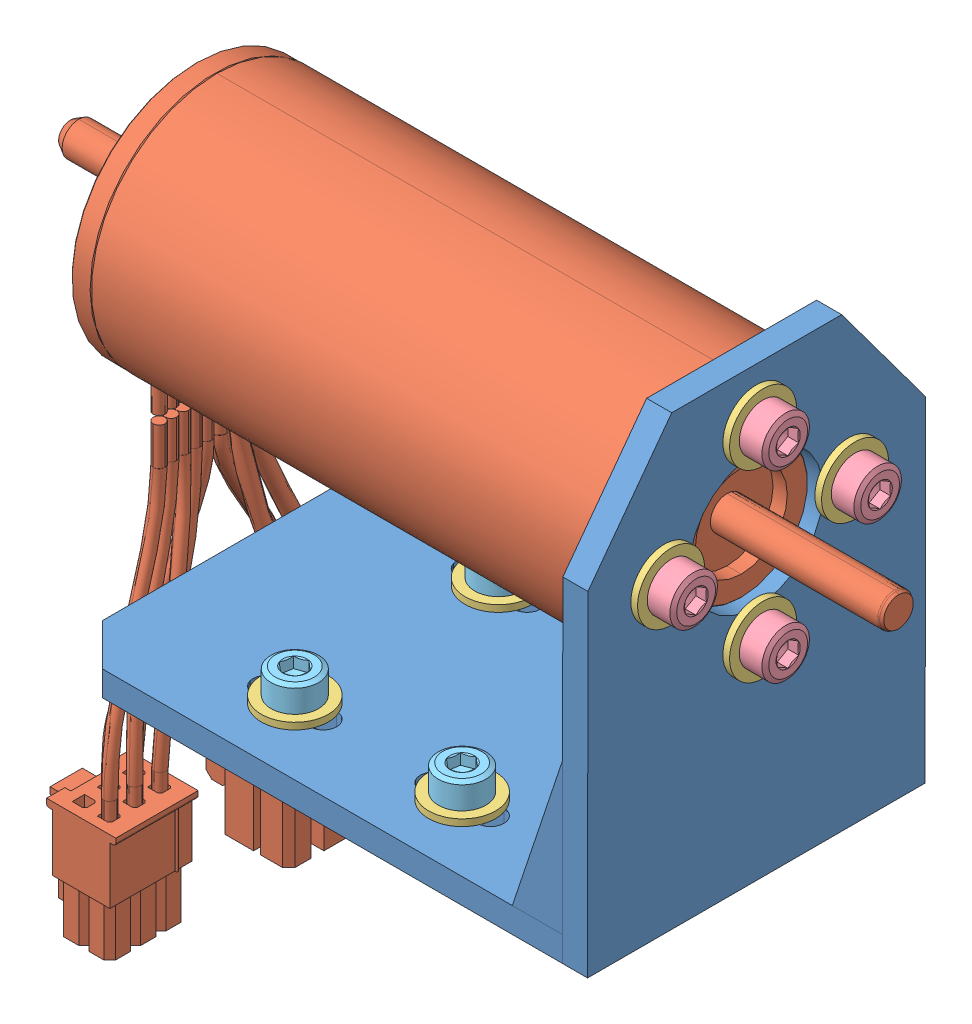
SolidWorks assembly Dc_Brushless_Assembly, configuration Default. Lengths in mm.
Overall size (99 86.67 40.4).
18 component instances, 5 part files, 35 mates.
Components (placement in the parent):
- DC_Brushless_mount-1: DC_Brushless_mount [Default] at (31.1622 81.4943 68.2509) x (0 0 1) z (0 -1 0) size (40.4 63 53.49)
- DC_Brushless_272762_ec-max30_60w.stp-1: DC_Brushless_272762_ec-max30_60w.stp [Default] at (19.2622 35.7216 38.1991) x (-1 0 0) z (0 0 -1) size (99 84.66 30.24)
- M3_95610A330_Nylon Plastic Washer-1: M3_95610A330_Nylon Plastic Washer [95610A330] at (31.5622 24.7216 38.1991) x (0 0.253843 0.967245) z (-1 0 0) size (8 8 0.8)
- M3_95610A330_Nylon Plastic Washer-2: M3_95610A330_Nylon Plastic Washer [95610A330] at (31.5622 35.7216 27.1991) x (0 0.155172 0.987888) z (-1 0 0) size (8 8 0.8)
- M3_95610A330_Nylon Plastic Washer-3: M3_95610A330_Nylon Plastic Washer [95610A330] at (31.5622 46.7216 38.1991) x (0 0 1) z (-1 0 0) size (8 8 0.8)
- M3_95610A330_Nylon Plastic Washer-4: M3_95610A330_Nylon Plastic Washer [95610A330] at (31.5622 35.7216 49.1991) x (0 0.252411 0.96762) z (-1 0 0) size (8 8 0.8)
- M3_8mm_98511A729_Aluminum Socket Head Screw (1)-1: M3_8mm_98511A729_Aluminum Socket Head Screw (1) [98511A729] at (29.4622 24.7216 38.1991) size (11.32 5.68 5.68)
- M3_8mm_98511A729_Aluminum Socket Head Screw (1)-2: M3_8mm_98511A729_Aluminum Socket Head Screw (1) [98511A729] at (29.4622 35.7216 49.1991) size (11.32 5.68 5.68)
- M3_8mm_98511A729_Aluminum Socket Head Screw (1)-3: M3_8mm_98511A729_Aluminum Socket Head Screw (1) [98511A729] at (29.4622 46.7216 38.1991) size (11.32 5.68 5.68)
- M3_8mm_98511A729_Aluminum Socket Head Screw (1)-4: M3_8mm_98511A729_Aluminum Socket Head Screw (1) [98511A729] at (29.4622 35.7216 27.1991) size (11.32 5.68 5.68)
- M3_95610A330_Nylon Plastic Washer-5: M3_95610A330_Nylon Plastic Washer [95610A330] at (8.1622 2.8005 50.3742) x (0.855074 0 0.518506) z (0 -1 0) size (8 8 0.8)
- M3_95610A330_Nylon Plastic Washer-6: M3_95610A330_Nylon Plastic Washer [95610A330] at (-11.8378 2.8005 50.3742) x (0.983199 0 -0.182536) z (0 -1 0) size (8 8 0.8)
- M3_95610A330_Nylon Plastic Washer-7: M3_95610A330_Nylon Plastic Washer [95610A330] at (8.1622 2.8005 26.0208) x (0.851879 0 0.523738) z (0 -1 0) size (8 8 0.8)
- M3_95610A330_Nylon Plastic Washer-8: M3_95610A330_Nylon Plastic Washer [95610A330] at (-11.8378 2.8005 26.0208) x (0.977128 0 0.212653) z (0 -1 0) size (8 8 0.8)
- M3_10mm_98511A731_Aluminum Socket Head Screw-1: M3_10mm_98511A731_Aluminum Socket Head Screw [98511A731] at (8.1622 -0.2995 50.3742) x (0 1 0) z (0.631898 0 -0.775052) size (13.33 5.68 5.68)
- M3_10mm_98511A731_Aluminum Socket Head Screw-2: M3_10mm_98511A731_Aluminum Socket Head Screw [98511A731] at (8.1622 -0.2995 26.0208) x (0 1 0) z (0.638158 0 0.769905) size (13.33 5.68 5.68)
- M3_10mm_98511A731_Aluminum Socket Head Screw-3: M3_10mm_98511A731_Aluminum Socket Head Screw [98511A731] at (-11.8378 -0.2995 50.3742) x (0 1 0) z (0.983429 0 0.181292) size (13.33 5.68 5.68)
- M3_10mm_98511A731_Aluminum Socket Head Screw-4: M3_10mm_98511A731_Aluminum Socket Head Screw [98511A731] at (-11.8378 -0.2995 26.0208) x (0 1 0) z (-0.583552 0 -0.812076) size (13.33 5.68 5.68)
Mates (geometry in assembly coordinates):
- Concentric1: concentric aligned: cylinder of DC_Brushless_mount-1 through (28.1622 35.7216 38.1991) axis (1 0 0) radius 8; cylinder of DC_Brushless_272762_ec-max30_60w.stp-1 through (18.7572 35.7216 38.1991) axis (1 0 0) radius 8
- Concentric2: concentric aligned: cylinder of DC_Brushless_mount-1 through (28.1622 46.7216 38.1991) axis (1 0 0) radius 1.6; cylinder of DC_Brushless_272762_ec-max30_60w.stp-1 through (17.7567 46.7216 38.1991) axis (1 0 0) radius 1.25
- Coincident1: coincident anti-aligned: plane of DC_Brushless_mount-1 through (28.1622 81.4943 68.2509) normal (-1 0 0); plane of DC_Brushless_272762_ec-max30_60w.stp-1 through (28.1622 35.7216 38.1991) normal (1 0 0)
- Concentric3: concentric aligned: cylinder of M3_95610A330_Nylon Plastic Washer-4 through (31.1622 35.7216 49.1991) axis (1 0 0) radius 1.6; cylinder of M3_8mm_98511A729_Aluminum Socket Head Screw (1)-2 through (34.9622 35.7216 49.1991) axis (1 0 0) radius 1.5
- Concentric4: concentric aligned: cylinder of M3_95610A330_Nylon Plastic Washer-3 through (31.1622 46.7216 38.1991) axis (1 0 0) radius 1.6; cylinder of M3_8mm_98511A729_Aluminum Socket Head Screw (1)-3 through (34.9622 46.7216 38.1991) axis (1 0 0) radius 1.5
- Concentric5: concentric aligned: cylinder of M3_95610A330_Nylon Plastic Washer-1 through (31.1622 24.7216 38.1991) axis (1 0 0) radius 1.6; cylinder of M3_8mm_98511A729_Aluminum Socket Head Screw (1)-1 through (34.9622 24.7216 38.1991) axis (1 0 0) radius 1.5
- Concentric6: concentric aligned: cylinder of M3_95610A330_Nylon Plastic Washer-2 through (31.1622 35.7216 27.1991) axis (1 0 0) radius 1.6; cylinder of M3_8mm_98511A729_Aluminum Socket Head Screw (1)-4 through (34.9622 35.7216 27.1991) axis (1 0 0) radius 1.5
- Coincident3: coincident anti-aligned: plane of M3_95610A330_Nylon Plastic Washer-2 through (31.9622 35.7216 27.1991) normal (1 0 0); plane of M3_8mm_98511A729_Aluminum Socket Head Screw (1)-4 through (31.9622 38.5616 27.1991) normal (-1 0 0)
- Coincident4: coincident anti-aligned: plane of M3_95610A330_Nylon Plastic Washer-1 through (31.9622 24.7216 38.1991) normal (1 0 0); plane of M3_8mm_98511A729_Aluminum Socket Head Screw (1)-1 through (31.9622 27.5616 38.1991) normal (-1 0 0)
- Coincident5: coincident anti-aligned: plane of M3_95610A330_Nylon Plastic Washer-3 through (31.9622 46.7216 38.1991) normal (1 0 0); plane of M3_8mm_98511A729_Aluminum Socket Head Screw (1)-3 through (31.9622 49.5616 38.1991) normal (-1 0 0)
- Coincident6: coincident anti-aligned: plane of M3_95610A330_Nylon Plastic Washer-4 through (31.9622 35.7216 49.1991) normal (1 0 0); plane of M3_8mm_98511A729_Aluminum Socket Head Screw (1)-2 through (31.9622 38.5616 49.1991) normal (-1 0 0)
- Concentric7: concentric aligned: cylinder of DC_Brushless_mount-1 through (28.1622 35.7216 49.1991) axis (1 0 0) radius 1.6; cylinder of M3_8mm_98511A729_Aluminum Socket Head Screw (1)-2 through (34.9622 35.7216 49.1991) axis (1 0 0) radius 1.5
- Concentric8: concentric aligned: cylinder of DC_Brushless_mount-1 through (28.1622 46.7216 38.1991) axis (1 0 0) radius 1.6; cylinder of M3_8mm_98511A729_Aluminum Socket Head Screw (1)-3 through (34.9622 46.7216 38.1991) axis (1 0 0) radius 1.5
- Concentric9: concentric aligned: cylinder of DC_Brushless_272762_ec-max30_60w.stp-1 through (17.7567 35.7216 27.1991) axis (1 0 0) radius 1.25; cylinder of M3_8mm_98511A729_Aluminum Socket Head Screw (1)-4 through (34.9622 35.7216 27.1991) axis (1 0 0) radius 1.5
- Concentric10: concentric aligned: cylinder of DC_Brushless_272762_ec-max30_60w.stp-1 through (17.7567 24.7216 38.1991) axis (1 0 0) radius 1.25; cylinder of M3_8mm_98511A729_Aluminum Socket Head Screw (1)-1 through (34.9622 24.7216 38.1991) axis (1 0 0) radius 1.5
- Coincident7: coincident anti-aligned: plane of DC_Brushless_mount-1 through (31.1622 81.4943 68.2509) normal (1 0 0); plane of M3_95610A330_Nylon Plastic Washer-1 through (31.1622 24.7216 38.1991) normal (-1 0 0)
- Coincident8: coincident anti-aligned: plane of DC_Brushless_mount-1 through (31.1622 81.4943 68.2509) normal (1 0 0); plane of M3_95610A330_Nylon Plastic Washer-4 through (31.1622 35.7216 49.1991) normal (-1 0 0)
- Coincident9: coincident anti-aligned: plane of DC_Brushless_mount-1 through (31.1622 81.4943 68.2509) normal (1 0 0); plane of M3_95610A330_Nylon Plastic Washer-2 through (31.1622 35.7216 27.1991) normal (-1 0 0)
- Coincident10: coincident anti-aligned: plane of DC_Brushless_mount-1 through (31.1622 81.4943 68.2509) normal (1 0 0); plane of M3_95610A330_Nylon Plastic Washer-3 through (31.1622 46.7216 38.1991) normal (-1 0 0)
- Concentric11: concentric aligned: cylinder of M3_95610A330_Nylon Plastic Washer-7 through (8.1622 2.4005 26.0208) axis (0 1 0) radius 1.6; cylinder of M3_10mm_98511A731_Aluminum Socket Head Screw-2 through (8.1622 6.2005 26.0208) axis (0 1 0) radius 1.5
- Concentric12: concentric aligned: cylinder of M3_95610A330_Nylon Plastic Washer-5 through (8.1622 2.4005 50.3742) axis (0 1 0) radius 1.6; cylinder of M3_10mm_98511A731_Aluminum Socket Head Screw-1 through (8.1622 6.2005 50.3742) axis (0 1 0) radius 1.5
- Concentric13: concentric aligned: cylinder of M3_95610A330_Nylon Plastic Washer-8 through (-11.8378 2.4005 26.0208) axis (0 1 0) radius 1.6; cylinder of M3_10mm_98511A731_Aluminum Socket Head Screw-4 through (-11.8378 6.2005 26.0208) axis (0 1 0) radius 1.5
- Concentric14: concentric aligned: cylinder of M3_95610A330_Nylon Plastic Washer-6 through (-11.8378 2.4005 50.3742) axis (0 1 0) radius 1.6; cylinder of M3_10mm_98511A731_Aluminum Socket Head Screw-3 through (-11.8378 6.2005 50.3742) axis (0 1 0) radius 1.5
- Coincident11: coincident anti-aligned: plane of M3_95610A330_Nylon Plastic Washer-7 through (8.1622 3.2005 26.0208) normal (0 1 0); plane of M3_10mm_98511A731_Aluminum Socket Head Screw-2 through (5.9757 3.2005 27.8332) normal (0 -1 0)
- Coincident12: coincident anti-aligned: plane of M3_95610A330_Nylon Plastic Washer-5 through (8.1622 3.2005 50.3742) normal (0 1 0); plane of M3_10mm_98511A731_Aluminum Socket Head Screw-1 through (10.3634 3.2005 52.1688) normal (0 -1 0)
- Coincident13: coincident anti-aligned: plane of M3_95610A330_Nylon Plastic Washer-8 through (-11.8378 3.2005 26.0208) normal (0 1 0); plane of M3_10mm_98511A731_Aluminum Socket Head Screw-4 through (-9.5315 3.2005 24.3635) normal (0 -1 0)
- Coincident14: coincident anti-aligned: plane of M3_95610A330_Nylon Plastic Washer-6 through (-11.8378 3.2005 50.3742) normal (0 1 0); plane of M3_10mm_98511A731_Aluminum Socket Head Screw-3 through (-12.3526 3.2005 53.1672) normal (0 -1 0)
- Slot1: slot: cylinder of M3_10mm_98511A731_Aluminum Socket Head Screw-2 through (8.1622 6.2005 26.0208) axis (0 1 0) radius 1.5; plane of DC_Brushless_mount-1 through (4.7622 -0.7995 27.6208) normal (0 0 -1); cylinder of DC_Brushless_mount-1 through (4.7622 2.4005 26.0208) axis (0 1 0) radius 1.6
- Coincident15: coincident anti-aligned: plane of DC_Brushless_mount-1 through (-31.8378 2.4005 18.0208) normal (0 1 0); plane of M3_95610A330_Nylon Plastic Washer-7 through (8.1622 2.4005 26.0208) normal (0 -1 0)
- Coincident16: coincident anti-aligned: plane of DC_Brushless_mount-1 through (-31.8378 2.4005 18.0208) normal (0 1 0); plane of M3_95610A330_Nylon Plastic Washer-5 through (8.1622 2.4005 50.3742) normal (0 -1 0)
- Coincident17: coincident anti-aligned: plane of DC_Brushless_mount-1 through (-31.8378 2.4005 18.0208) normal (0 1 0); plane of M3_95610A330_Nylon Plastic Washer-8 through (-11.8378 2.4005 26.0208) normal (0 -1 0)
- Coincident18: coincident anti-aligned: plane of DC_Brushless_mount-1 through (-31.8378 2.4005 18.0208) normal (0 1 0); plane of M3_95610A330_Nylon Plastic Washer-6 through (-11.8378 2.4005 50.3742) normal (0 -1 0)
- Slot2: slot: cylinder of M3_10mm_98511A731_Aluminum Socket Head Screw-1 through (8.1622 6.2005 50.3742) axis (0 1 0) radius 1.5; plane of DC_Brushless_mount-1 through (4.7622 -0.7995 51.9742) normal (0 0 -1); cylinder of DC_Brushless_mount-1 through (4.7622 2.4005 50.3742) axis (0 1 0) radius 1.6
- Slot3: slot: cylinder of M3_10mm_98511A731_Aluminum Socket Head Screw-4 through (-11.8378 6.2005 26.0208) axis (0 1 0) radius 1.5; plane of DC_Brushless_mount-1 through (-15.2378 -0.7995 27.6208) normal (0 0 -1); cylinder of DC_Brushless_mount-1 through (-15.2378 2.4005 26.0208) axis (0 1 0) radius 1.6
- Slot4: slot: cylinder of M3_10mm_98511A731_Aluminum Socket Head Screw-3 through (-11.8378 6.2005 50.3742) axis (0 1 0) radius 1.5; plane of DC_Brushless_mount-1 through (-15.2378 -0.7995 51.9742) normal (0 0 -1); cylinder of DC_Brushless_mount-1 through (-15.2378 2.4005 50.3742) axis (0 1 0) radius 1.6
